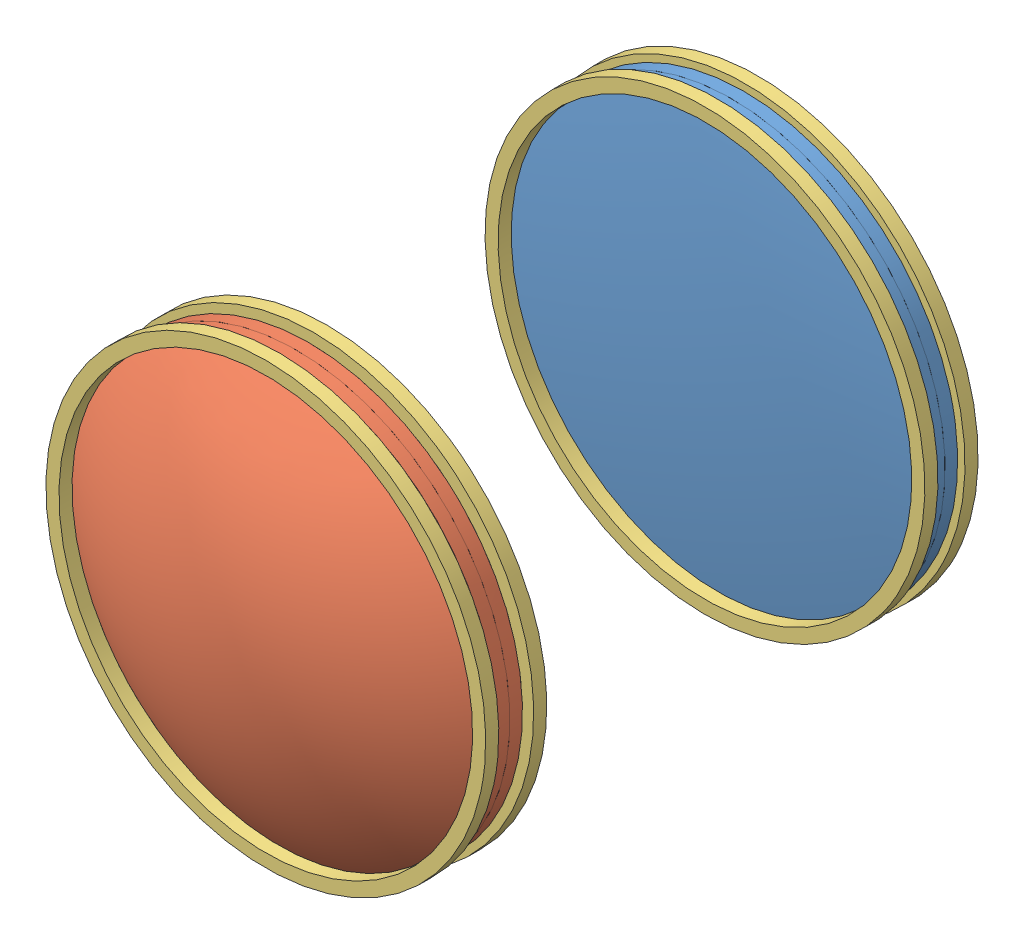
SolidWorks assembly Lens Mount with lenses, configuration Default. Lengths in mm.
Overall size (82.39 82.39 64.91).
13 component instances, 6 part files, 10 mates.
Components (placement in the parent):
- 200 mm lens-1: 200 mm lens [Default] at (-70.0583 -42.8052 135.7184) x (0.984022 -0.178049 0) z (0 0 1) size (66.38 66.38 6.55)
  - 200 mm lens half-1: 200 mm lens half [Default] at (89.9388 90.4266 -92.3673) size (50.8 50.8 3.28)
  - 200 mm lens half-2: 200 mm lens half [Default] at (89.9388 90.4266 266.2247) x (-0.923728 -0.383049 0) z (0 0 -1) size (50.8 50.8 3.28)
- Lens Tube Upper-1: Lens Tube Upper [Default] at (30.7965 12.3973 0) x (0.721097 0.692835 0) z (0 0 1) (suppressed, hidden)
- Lens Tube Lower-1: Lens Tube Lower [Default] at origin (suppressed, hidden)
- 50.2 mm lense-1: 50.2 mm lense [Default] at (19.5577 -8.6041 212.336) x (0.91524 0.402909 0) z (0 0 1) size (66.38 66.38 19.74)
  - 50.2 mm lens half-1: 50.2 mm lens half [Default] at (29.3355 29.4432 29.2096) size (50.8 50.8 9.87)
  - 50.2 mm lens half-2: 50.2 mm lens half [Default] at (29.3355 29.4432 94.9456) x (-0.923728 -0.383049 0) z (0 0 -1) size (50.8 50.8 9.87)
- Lens Ring-1: Lens Ring [Default] at (34.5438 30.163 270.782) x (0.605872 0.795562 0) z (0 0 1) size (52.32 52.32 1.56)
- Lens Ring-2: Lens Ring [Default] at (34.5438 30.163 276.4894) x (0.98796 -0.154713 0) z (0 0 1) size (52.32 52.32 1.56)
- Lens Ring-3: Lens Ring [Default] at (34.5438 30.163 224.2563) x (0.843294 -0.537453 0) z (0 0 1) size (52.32 52.32 1.56)
- Lens Ring-4: Lens Ring [Default] at (34.5438 30.163 219.482) x (0.900841 -0.434149 0) z (0 0 1) size (52.32 52.32 1.56)
- Ruler-1: Ruler [Default] at (25.4 5.08 279.4) (suppressed, hidden)
Mates (geometry in assembly coordinates):
- Coincident1: coincident anti-aligned: axis of 50.2 mm lense-1/50.2 mm lens half-1 through (34.5438 30.163 274.4136) axis (0 0 1); axis of Lens Ring-2 through (34.5438 30.163 278.0451) axis (0 0 -1)
- Coincident2: coincident aligned: axis of 50.2 mm lense-1/50.2 mm lens half-2 through (34.5438 30.163 274.4136) axis (0 0 -1); axis of Lens Ring-1 through (34.5438 30.163 272.3378) axis (0 0 -1)
- Coincident3: coincident aligned: axis of 200 mm lens-1/200 mm lens half-2 through (34.5438 30.163 222.647) axis (0 0 -1); axis of Lens Ring-4 through (34.5438 30.163 221.0378) axis (0 0 -1)
- Coincident4: coincident anti-aligned: axis of 200 mm lens-1/200 mm lens half-1 through (34.5438 30.163 222.647) axis (0 0 1); axis of Lens Ring-3 through (34.5438 30.163 225.812) axis (0 0 -1)
- Concentric1: concentric aligned: circle of 200 mm lens-1/200 mm lens half-1; circle of Lens Ring-3
- Tangent1: tangent: sphere of 50.2 mm lense-1/50.2 mm lens half-1; circle of Lens Ring-2
- Tangent2: tangent: sphere of 50.2 mm lense-1/50.2 mm lens half-2; circle of Lens Ring-1
- Tangent3: tangent: sphere of 200 mm lens-1/200 mm lens half-1; circle of Lens Ring-3
- Tangent4: tangent: sphere of 200 mm lens-1/200 mm lens half-2; circle of Lens Ring-4
- Coincident5: coincident aligned: axis of 50.2 mm lense-1/50.2 mm lens half-2 through (34.5438 30.163 274.4136) axis (0 0 -1); axis of Lens Ring-3 through (34.5438 30.163 225.812) axis (0 0 -1)
